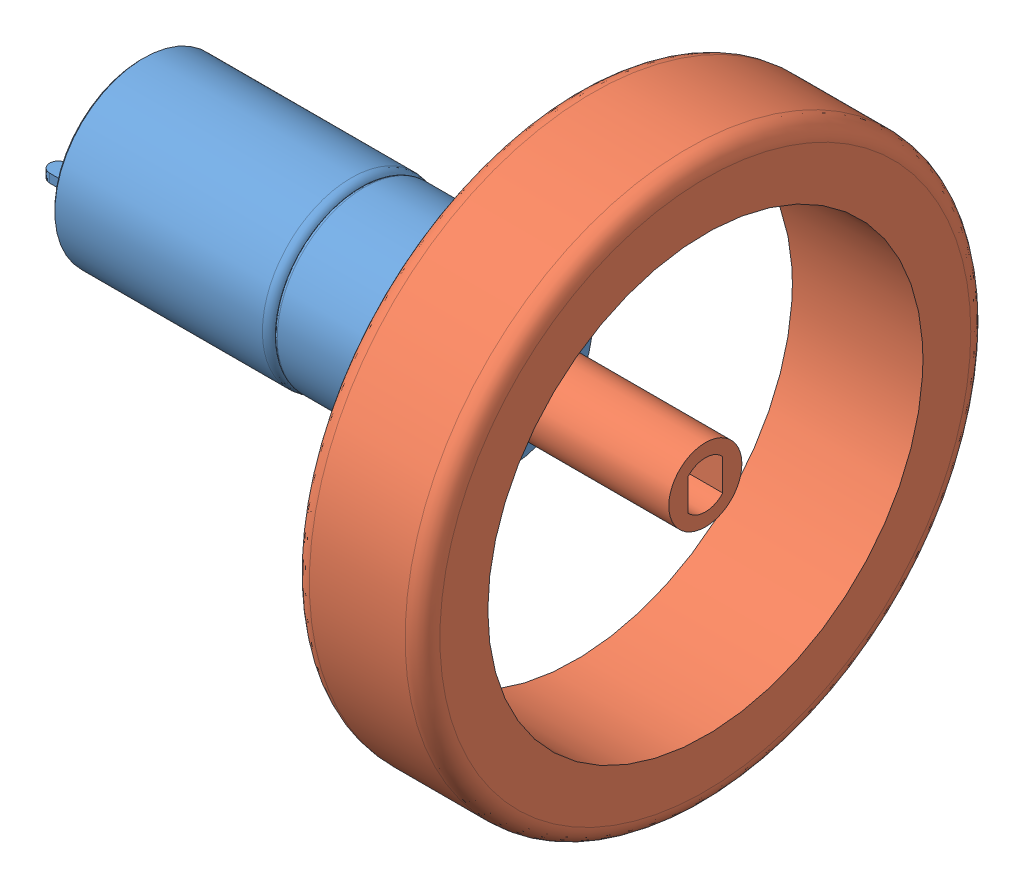
SolidWorks assembly Motor Thin Wheel Assembly, configuration Default. Lengths in mm.
Overall size (69.19 65 65).
2 component instances, 2 part files, 1 mates.
Components (placement in the parent):
- DC Motor-1: DC Motor [Default] at origin size (57.5 20.4 20.4)
- 3763 Thin Wheel-1: 3763 Thin Wheel [Default] at (57.2938 0 0) x (0 0 -1) z (1 0 0) size (65 65 18.85)
Mates (geometry in assembly coordinates):
- Concentric1: concentric anti-aligned: cylinder of DC Motor-1 through (53.1 0 0) axis (-1 0 0) radius 2; cylinder of 3763 Thin Wheel-1 through (30.2144 0 0) axis (1 0 0) radius 4.2
